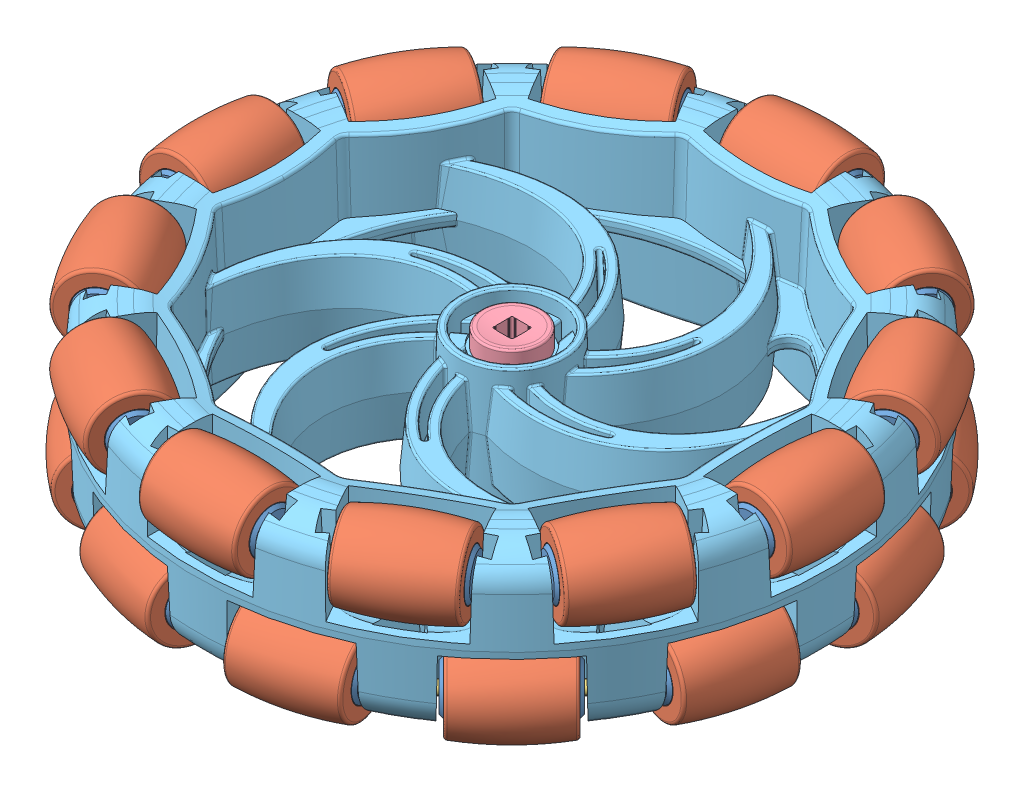
SolidWorks assembly 4in Omni Directional Wheel, configuration Default. Lengths in mm.
Overall size (108.3 29.85 108.3).
98 component instances, 5 part files, 0 mates.
Components (placement in the parent):
- OMNI-ROLLER-1: OMNI-ROLLER [Default] at (23.2326 8 -40.2802) x (0.866025 0 0.5) z (-0.5 0 0.866025) size (22 13.22 13.22)
  - ROLLER-INSERT-1: ROLLER-INSERT [Default] at origin size (16.6 8 8)
  - ROLLER-RUBBER-1: ROLLER-RUBBER [Default] at origin size (15.6 13.22 13.22)
  - ROLLER-SHAFT-1: ROLLER-SHAFT [Default] at origin size (22 2 2)
- OMNI-ROLLER-2: OMNI-ROLLER [Default] at (40.2671 8 23.2553) x (0.5 0 -0.866025) z (0.866025 0 0.5) size (22 13.22 13.22)
  - ROLLER-INSERT-1: ROLLER-INSERT [Default] at origin size (16.6 8 8)
  - ROLLER-RUBBER-1: ROLLER-RUBBER [Default] at origin size (15.6 13.22 13.22)
  - ROLLER-SHAFT-1: ROLLER-SHAFT [Default] at origin size (22 2 2)
- OMNI-ROLLER-3: OMNI-ROLLER [Default] at (0.013 8 46.5) size (22 13.22 13.22)
  - ROLLER-INSERT-1: ROLLER-INSERT [Default] at origin size (16.6 8 8)
  - ROLLER-RUBBER-1: ROLLER-RUBBER [Default] at origin size (15.6 13.22 13.22)
  - ROLLER-SHAFT-1: ROLLER-SHAFT [Default] at origin size (22 2 2)
- OMNI-ROLLER-4: OMNI-ROLLER [Default] at (12.0398 -8 44.9143) x (0.965926 0 -0.258819) z (0.258819 0 0.965926) size (22 13.22 13.22)
  - ROLLER-INSERT-1: ROLLER-INSERT [Default] at origin size (16.6 8 8)
  - ROLLER-RUBBER-1: ROLLER-RUBBER [Default] at origin size (15.6 13.22 13.22)
  - ROLLER-SHAFT-1: ROLLER-SHAFT [Default] at origin size (22 2 2)
- OMNI-ROLLER-5: OMNI-ROLLER [Default] at (44.9116 -8 -12.0497) x (0.258819 0 0.965926) z (-0.965926 0 0.258819) size (22 13.22 13.22)
  - ROLLER-INSERT-1: ROLLER-INSERT [Default] at origin size (16.6 8 8)
  - ROLLER-RUBBER-1: ROLLER-RUBBER [Default] at origin size (15.6 13.22 13.22)
  - ROLLER-SHAFT-1: ROLLER-SHAFT [Default] at origin size (22 2 2)
- OMNI-ROLLER-6: OMNI-ROLLER [Default] at (-12.0287 -8 -44.9173) x (0.965926 0 -0.258819) z (0.258819 0 0.965926) size (22 13.22 13.22)
  - ROLLER-INSERT-1: ROLLER-INSERT [Default] at origin size (16.6 8 8)
  - ROLLER-RUBBER-1: ROLLER-RUBBER [Default] at origin size (15.6 13.22 13.22)
  - ROLLER-SHAFT-1: ROLLER-SHAFT [Default] at origin size (22 2 2)
- OMNI-ROLLER-7: OMNI-ROLLER [Default] at (-23.2609 8 40.2639) x (0.866025 0 0.5) z (-0.5 0 0.866025) size (22 13.22 13.22)
  - ROLLER-INSERT-1: ROLLER-INSERT [Default] at origin size (16.6 8 8)
  - ROLLER-RUBBER-1: ROLLER-RUBBER [Default] at origin size (15.6 13.22 13.22)
  - ROLLER-SHAFT-1: ROLLER-SHAFT [Default] at origin size (22 2 2)
- OMNI-ROLLER-8: OMNI-ROLLER [Default] at (-12.0305 -8 44.9168) x (0.965926 0 0.258819) z (-0.258819 0 0.965926) size (22 13.22 13.22)
  - ROLLER-INSERT-1: ROLLER-INSERT [Default] at origin size (16.6 8 8)
  - ROLLER-RUBBER-1: ROLLER-RUBBER [Default] at origin size (15.6 13.22 13.22)
  - ROLLER-SHAFT-1: ROLLER-SHAFT [Default] at origin size (22 2 2)
- OMNI-ROLLER-9: OMNI-ROLLER [Default] at (12.0345 -8 -44.9157) x (0.965926 0 0.258819) z (-0.258819 0 0.965926) size (22 13.22 13.22)
  - ROLLER-INSERT-1: ROLLER-INSERT [Default] at origin size (16.6 8 8)
  - ROLLER-RUBBER-1: ROLLER-RUBBER [Default] at origin size (15.6 13.22 13.22)
  - ROLLER-SHAFT-1: ROLLER-SHAFT [Default] at origin size (22 2 2)
- OMNI-ROLLER-10: OMNI-ROLLER [Default] at (-40.2754 8 23.241) x (0.5 0 0.866025) z (-0.866025 0 0.5) size (22 13.22 13.22)
  - ROLLER-INSERT-1: ROLLER-INSERT [Default] at origin size (16.6 8 8)
  - ROLLER-RUBBER-1: ROLLER-RUBBER [Default] at origin size (15.6 13.22 13.22)
  - ROLLER-SHAFT-1: ROLLER-SHAFT [Default] at origin size (22 2 2)
- OMNI-ROLLER-11: OMNI-ROLLER [Default] at (-40.2738 8 -23.2437) x (0.5 0 -0.866025) z (0.866025 0 0.5) size (22 13.22 13.22)
  - ROLLER-INSERT-1: ROLLER-INSERT [Default] at origin size (16.6 8 8)
  - ROLLER-RUBBER-1: ROLLER-RUBBER [Default] at origin size (15.6 13.22 13.22)
  - ROLLER-SHAFT-1: ROLLER-SHAFT [Default] at origin size (22 2 2)
- OMNI-ROLLER-12: OMNI-ROLLER [Default] at (46.5 8 0) x (0 0 1) z (0 1 0) size (22 13.22 13.22)
  - ROLLER-INSERT-1: ROLLER-INSERT [Default] at origin size (16.6 8 8)
  - ROLLER-RUBBER-1: ROLLER-RUBBER [Default] at origin size (15.6 13.22 13.22)
  - ROLLER-SHAFT-1: ROLLER-SHAFT [Default] at origin size (22 2 2)
- OMNI-ROLLER-13: OMNI-ROLLER [Default] at (-0.0255 8 -46.5) size (22 13.22 13.22)
  - ROLLER-INSERT-1: ROLLER-INSERT [Default] at origin size (16.6 8 8)
  - ROLLER-RUBBER-1: ROLLER-RUBBER [Default] at origin size (15.6 13.22 13.22)
  - ROLLER-SHAFT-1: ROLLER-SHAFT [Default] at origin size (22 2 2)
- OMNI-ROLLER-14: OMNI-ROLLER [Default] at (23.2429 8 40.2743) x (0.866025 0 -0.5) z (0.5 0 0.866025) size (22 13.22 13.22)
  - ROLLER-INSERT-1: ROLLER-INSERT [Default] at origin size (16.6 8 8)
  - ROLLER-RUBBER-1: ROLLER-RUBBER [Default] at origin size (15.6 13.22 13.22)
  - ROLLER-SHAFT-1: ROLLER-SHAFT [Default] at origin size (22 2 2)
- OMNI-ROLLER-15: OMNI-ROLLER [Default] at (-44.9187 -8 12.0234) x (0.258819 0 0.965926) z (-0.965926 0 0.258819) size (22 13.22 13.22)
  - ROLLER-INSERT-1: ROLLER-INSERT [Default] at origin size (16.6 8 8)
  - ROLLER-RUBBER-1: ROLLER-RUBBER [Default] at origin size (15.6 13.22 13.22)
  - ROLLER-SHAFT-1: ROLLER-SHAFT [Default] at origin size (22 2 2)
- OMNI-ROLLER-16: OMNI-ROLLER [Default] at (-44.9129 -8 -12.0449) x (0.258819 0 -0.965926) z (0.965926 0 0.258819) size (22 13.22 13.22)
  - ROLLER-INSERT-1: ROLLER-INSERT [Default] at origin size (16.6 8 8)
  - ROLLER-RUBBER-1: ROLLER-RUBBER [Default] at origin size (15.6 13.22 13.22)
  - ROLLER-SHAFT-1: ROLLER-SHAFT [Default] at origin size (22 2 2)
- OMNI-ROLLER-17: OMNI-ROLLER [Default] at (-23.2538 8 -40.268) x (0.866025 0 -0.5) z (0.5 0 0.866025) size (22 13.22 13.22)
  - ROLLER-INSERT-1: ROLLER-INSERT [Default] at origin size (16.6 8 8)
  - ROLLER-RUBBER-1: ROLLER-RUBBER [Default] at origin size (15.6 13.22 13.22)
  - ROLLER-SHAFT-1: ROLLER-SHAFT [Default] at origin size (22 2 2)
- OMNI-ROLLER-18: OMNI-ROLLER [Default] at (32.8529 -8 -32.9081) x (0.707107 0 0.707107) z (-0.707107 0 0.707107) size (22 13.22 13.22)
  - ROLLER-INSERT-1: ROLLER-INSERT [Default] at origin size (16.6 8 8)
  - ROLLER-RUBBER-1: ROLLER-RUBBER [Default] at origin size (15.6 13.22 13.22)
  - ROLLER-SHAFT-1: ROLLER-SHAFT [Default] at origin size (22 2 2)
- OMNI-ROLLER-19: OMNI-ROLLER [Default] at (40.2648 8 -23.2593) x (0.5 0 0.866025) z (-0.866025 0 0.5) size (22 13.22 13.22)
  - ROLLER-INSERT-1: ROLLER-INSERT [Default] at origin size (16.6 8 8)
  - ROLLER-RUBBER-1: ROLLER-RUBBER [Default] at origin size (15.6 13.22 13.22)
  - ROLLER-SHAFT-1: ROLLER-SHAFT [Default] at origin size (22 2 2)
- LARGE-OMNI-HUB-INSERT-1: LARGE-OMNI-HUB-INSERT [Default] x (-1 0 0) z (0 1 0) size (9.68 9.68 19.05)
- OMNI-ROLLER-20: OMNI-ROLLER [Default] at (32.8647 -8 32.8962) x (0.707107 0 -0.707107) z (0.707107 0 0.707107) size (22 13.22 13.22)
  - ROLLER-INSERT-1: ROLLER-INSERT [Default] at origin size (16.6 8 8)
  - ROLLER-RUBBER-1: ROLLER-RUBBER [Default] at origin size (15.6 13.22 13.22)
  - ROLLER-SHAFT-1: ROLLER-SHAFT [Default] at origin size (22 2 2)
- OMNI-ROLLER-21: OMNI-ROLLER [Default] at (44.9169 -8 12.0301) x (0.258819 0 -0.965926) z (0.965926 0 0.258819) size (22 13.22 13.22)
  - ROLLER-INSERT-1: ROLLER-INSERT [Default] at origin size (16.6 8 8)
  - ROLLER-RUBBER-1: ROLLER-RUBBER [Default] at origin size (15.6 13.22 13.22)
  - ROLLER-SHAFT-1: ROLLER-SHAFT [Default] at origin size (22 2 2)
- LARGE-OMNI-HUB-1: LARGE-OMNI-HUB [Default] at origin size (102 28.49 102)
- OMNI-ROLLER-22: OMNI-ROLLER [Default] at (-46.5 8 -0.0142) x (0 0 -1) z (1 0 0) size (22 13.22 13.22)
  - ROLLER-INSERT-1: ROLLER-INSERT [Default] at origin size (16.6 8 8)
  - ROLLER-RUBBER-1: ROLLER-RUBBER [Default] at origin size (15.6 13.22 13.22)
  - ROLLER-SHAFT-1: ROLLER-SHAFT [Default] at origin size (22 2 2)
- OMNI-ROLLER-23: OMNI-ROLLER [Default] at (-32.8835 -8 32.8775) x (0.707107 0 0.707107) z (-0.707107 0 0.707107) size (22 13.22 13.22)
  - ROLLER-INSERT-1: ROLLER-INSERT [Default] at origin size (16.6 8 8)
  - ROLLER-RUBBER-1: ROLLER-RUBBER [Default] at origin size (15.6 13.22 13.22)
  - ROLLER-SHAFT-1: ROLLER-SHAFT [Default] at origin size (22 2 2)
- OMNI-ROLLER-24: OMNI-ROLLER [Default] at (-32.8436 -8 -32.9173) x (0.707107 0 -0.707107) z (0.707107 0 0.707107) size (22 13.22 13.22)
  - ROLLER-INSERT-1: ROLLER-INSERT [Default] at origin size (16.6 8 8)
  - ROLLER-RUBBER-1: ROLLER-RUBBER [Default] at origin size (15.6 13.22 13.22)
  - ROLLER-SHAFT-1: ROLLER-SHAFT [Default] at origin size (22 2 2)
